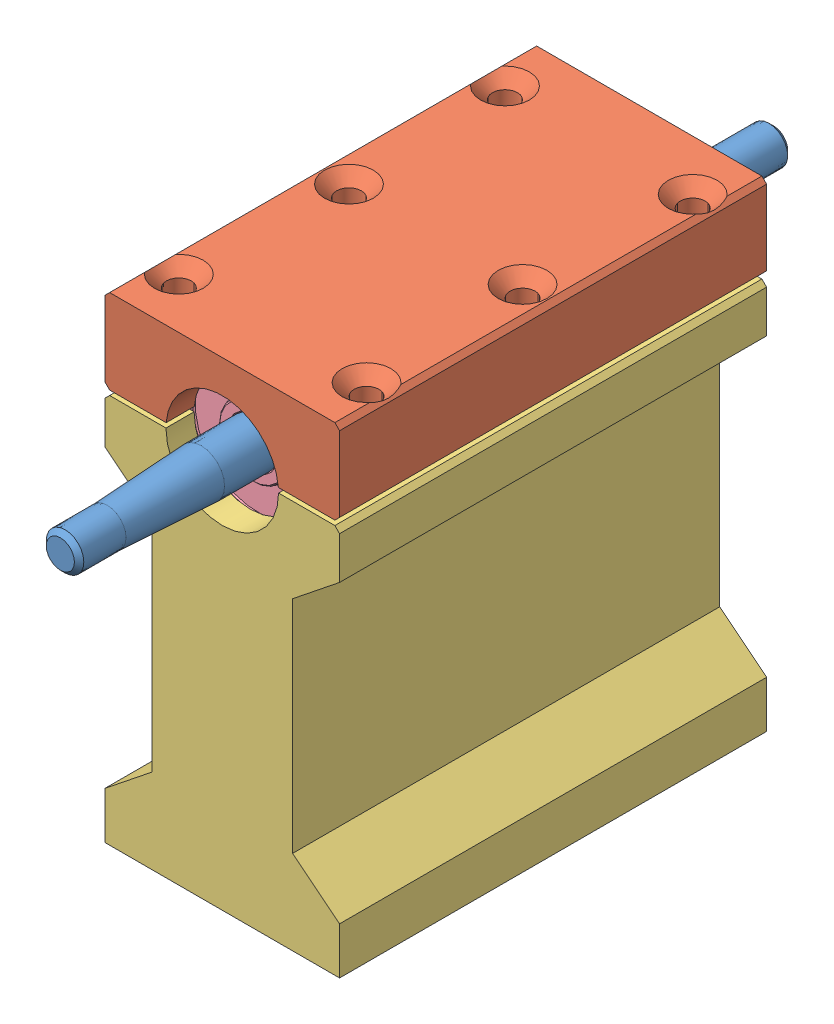
SolidWorks assembly back_axis, configuration Default. Lengths in mm.
Overall size (50.2 109.53 152).
7 component instances, 5 part files, 11 mates.
Components (placement in the parent):
- axis-1: axis [Spur01] at (46.6192 83.1455 68.5463) size (15 15 152)
- back_axis_cover-1: back_axis_cover [Default] at (46.6192 83.1455 84.0463) size (50.2 18.53 91)
- back_axis_support-1: back_axis_support [Default] at (46.6192 83.1455 84.0463) size (50 90 91)
- 7200 BEP-1: 7200 BEP [По умолчанию] at (46.6192 83.1455 -0.4537) size (30 30 9)
- 7200 BEP-2: 7200 BEP [По умолчанию] at (46.6192 83.1455 68.5463) size (30 30 9)
- Hex Nut 15521_gost-2: Hex Nut 15521_gost [Гайка M10x1,25 ГОСТ 15521-70] at (46.6192 83.1455 -8.4537) x (0.923728 0.383049 0) z (0 0 -1) size (16.17 14 8)
- Hex Nut 15521_gost-3: Hex Nut 15521_gost [Гайка M10x1,25 ГОСТ 15521-70] at (46.6192 83.1455 -16.4537) x (0.923728 0.383049 0) z (0 0 -1) size (16.17 14 8)
Mates (geometry in assembly coordinates):
- Концентричный1: concentric aligned: cylinder of back_axis_support-1 through (46.6192 83.1455 -6.9537) axis (0 0 1) radius 12; cylinder of axis-1 through (46.6192 83.1455 11.0463) axis (0 0 1) radius 5
- Совпадение5: coincident aligned: plane of axis-1 through (46.6192 83.1455 8.5463) normal (0 0 -1); plane of back_axis_support-1 through (58.6192 83.1455 8.5463) normal (0 0 -1)
- Совпадение4: coincident aligned: plane of back_axis_cover-1 through (46.6192 83.1455 -6.9537) normal (0 0 -1); plane of back_axis_support-1 through (46.6192 83.1455 -6.9537) normal (0 0 -1)
- Концентричный2: concentric anti-aligned: cylinder of axis-1 through (46.6192 83.1455 -18.4537) axis (0 0 1) radius 5; cylinder of 7200 BEP-1 through (46.6192 83.1455 8.5463) axis (0 0 -1) radius 5
- Совпадение6: coincident anti-aligned: plane of axis-1 through (46.6192 83.1455 8.5463) normal (0 0 -1); plane of 7200 BEP-1 through (46.6192 83.1455 8.5463) normal (0 0 1)
- Концентричный3: concentric aligned: cylinder of axis-1 through (46.6192 83.1455 88.5463) axis (0 0 -1) radius 5; cylinder of 7200 BEP-2 through (46.6192 83.1455 77.5463) axis (0 0 -1) radius 5
- Совпадение7: coincident anti-aligned: plane of axis-1 through (46.6192 83.1455 68.5463) normal (0 0 1); plane of 7200 BEP-2 through (46.6192 83.1455 68.5463) normal (0 0 -1)
- Концентричный4: concentric anti-aligned: cone of 7200 BEP-1 through (46.6192 83.1455 -0.2037) axis (0 0 1); cylinder of Hex Nut 15521_gost-2 through (46.6192 83.1455 -0.4537) axis (0 0 -1) radius 5
- Совпадение8: coincident anti-aligned: plane of 7200 BEP-1 through (46.6192 83.1455 -0.4537) normal (0 0 -1); plane of Hex Nut 15521_gost-2 through (51.9819 70.2133 -0.4537) normal (0 0 1)
- Концентричный5: concentric aligned: cylinder of Hex Nut 15521_gost-2 through (46.6192 83.1455 -0.4537) axis (0 0 -1) radius 5; cylinder of Hex Nut 15521_gost-3 through (46.6192 83.1455 -8.4537) axis (0 0 -1) radius 5
- Совпадение9: coincident anti-aligned: plane of Hex Nut 15521_gost-2 through (51.9819 70.2133 -8.4537) normal (0 0 -1); plane of Hex Nut 15521_gost-3 through (51.9819 70.2133 -8.4537) normal (0 0 1)
